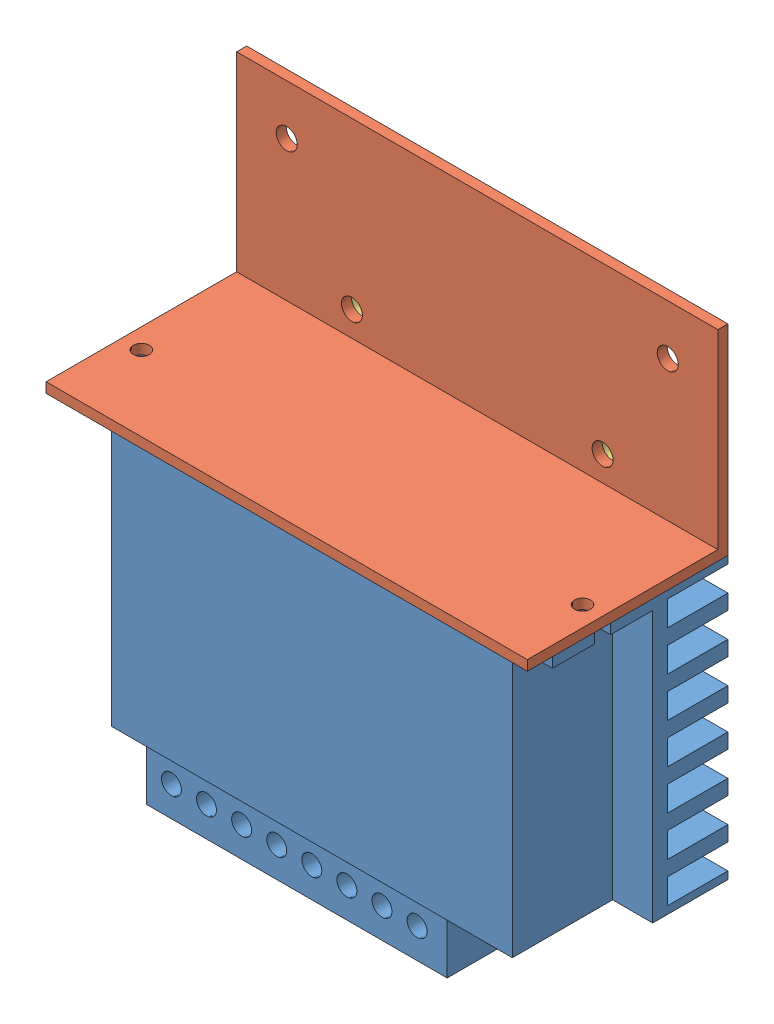
SolidWorks assembly Драйвер двигателя с креплением, configuration По умолчанию. Lengths in mm.
Overall size (96 108 51).
3 component instances, 3 part files, 10 mates.
Components (placement in the parent):
- Драйвер-1: Драйвер [По умолчанию] at origin size (96 68 35)
- Уголок 40x40 - 1-1: Уголок 40x40 - 1 [По умолчанию] at (96 56 0) x (0 0 1) z (-1 0 0) size (40 40 96)
- Вентиллятор-1: Вентиллятор [По умолчанию] at (18 68 0) x (1 0 0) z (0 0 -1) size (60 60 11)
Mates (geometry in assembly coordinates):
- Совпадение1: coincident aligned: plane of Драйвер-1 through (0 0 0) normal (0 0 1); plane of assembly through (0 0 0) normal (0 0 1)
- Совпадение2: coincident aligned: plane of Драйвер-1 through (0 0 0) normal (0 1 0); plane of assembly through (0 0 0) normal (0 1 0)
- Совпадение3: coincident aligned: plane of Драйвер-1 through (0 0 0) normal (1 0 0); plane of assembly through (0 0 0) normal (1 0 0)
- Совпадение4: coincident anti-aligned: plane of Драйвер-1 through (0 56 35) normal (0 1 0); plane of Уголок 40x40 - 1-1 through (0 56 0) normal (0 -1 0)
- Совпадение5: coincident aligned: plane of Драйвер-1 through (96 0 35) normal (1 0 0); plane of Уголок 40x40 - 1-1 through (96 56 0) normal (1 0 0)
- Совпадение6: coincident aligned: plane of Драйвер-1 through (0 0 0) normal (0 0 -1); plane of Уголок 40x40 - 1-1 through (0 96 0) normal (0 0 -1)
- Концентричный1: concentric anti-aligned: circle of Уголок 40x40 - 1-1; cylinder of Вентиллятор-1 through (23 63 -11) axis (0 0 1) radius 2.2
- Концентричный2: concentric anti-aligned: cylinder of Драйвер-1 through (23 13 15) axis (0 0 -1) radius 2.25; cylinder of Вентиллятор-1 through (23 13 -11) axis (0 0 1) radius 2.2
- Концентричный3: concentric anti-aligned: cylinder of Уголок 40x40 - 1-1 through (73 63 40) axis (0 0 -1) radius 2.25; cylinder of Вентиллятор-1 through (73 63 -11) axis (0 0 1) radius 2.2
- Совпадение7: coincident anti-aligned: plane of Уголок 40x40 - 1-1 through (0 96 0) normal (0 0 -1); plane of Вентиллятор-1 through (18 68 0) normal (0 0 1)
